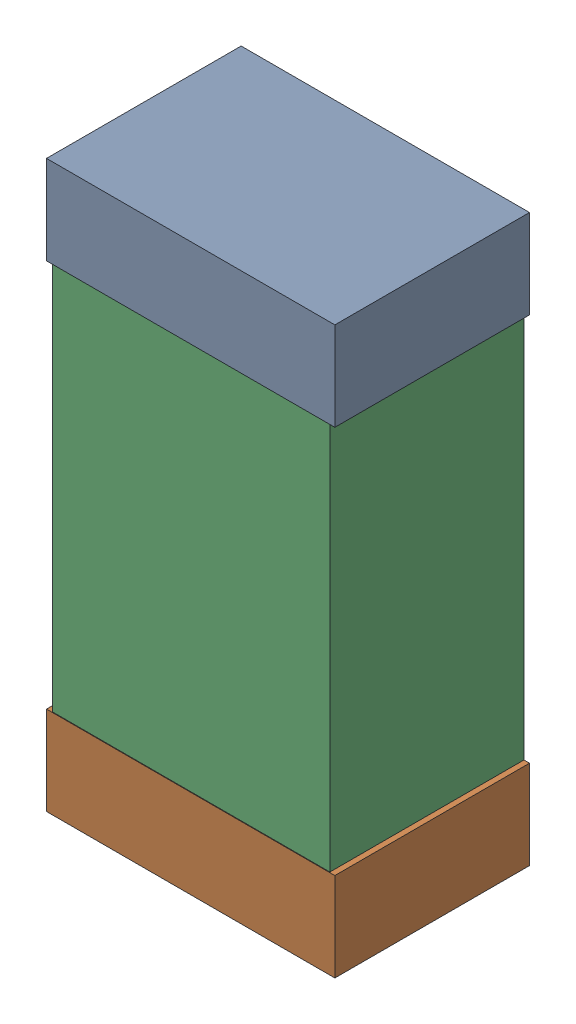
SolidWorks assembly C11, configuration Default. Lengths in mm.
Overall size (0.52 1.02 0.35).
6 component instances, 2 part files, 0 mates.
Components (placement in the parent):
- 870941120-1: 870941120 [Default] at (57.2508 25.4722 0) size (0.52 0.16 0.35)
  - Extruded_3-1: Extruded_3 [Default] at origin size (0.52 0.16 0.35)
- 870941120-2: 870941120 [Default] at (57.2508 24.6122 0) size (0.52 0.16 0.35)
  - Extruded_3-1: Extruded_3 [Default] at origin size (0.52 0.16 0.35)
- 870941280-1: 870941280 [Default] at (57.2508 25.0422 0) size (0.5 1 0.35)
  - Extruded_4-1: Extruded_4 [Default] at origin size (0.5 1 0.35)
